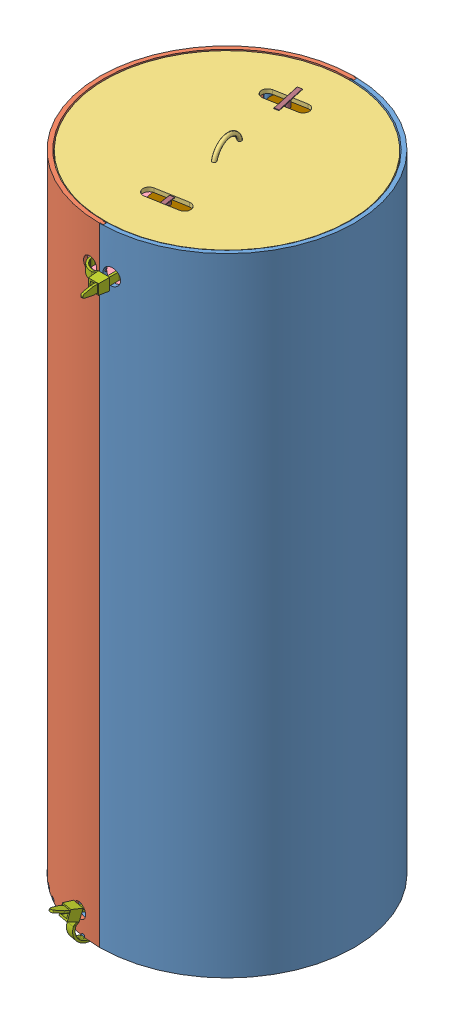
SolidWorks assembly Assemb_final, configuration Default. Lengths in mm.
Overall size (167.56 319.54 166.94).
85 component instances, 50 part files, 17 mates.
Components (placement in the parent):
- Part1-1: Part1 [Default] at (122.3324 -8.1399 242.6336) size (125 308 125)
- sec_cylinder-1: sec_cylinder [Default] at (122.3324 -8.1399 242.6336) size (64 308 125)
- Part2-1: Part2 [Default] at (-13.2425 297.5983 266.88) x (-0.176048 0 -0.984382) z (0.984382 0 -0.176048) size (120 9 120)
- Part3-1: Part3 [Default] at (123.4602 107.8147 242.6336) x (0.837662 0 -0.546189) z (0.546189 0 0.837662) size (120 1.5 120)
- Adafruit BMP388 Breakout.step-1: Adafruit BMP388 Breakout.step [Default] at (72.5042 113.6075 224.1927) size (21.59 11.6 16.51)
  - MalePinHeader.step-1: MalePinHeader.step [Default] at (14.8329 -4.1349 22.0117) size (2.54 11.54 2.54)
  - MalePinHeader.step-2: MalePinHeader.step [Default] at (9.7562 -4.1349 22.0162) size (2.54 11.54 2.54)
  - MalePinHeader.step-3: MalePinHeader.step [Default] at (7.2156 -4.1349 21.9989) size (2.54 11.54 2.54)
  - MalePinHeader.step-4: MalePinHeader.step [Default] at (-0.4008 -4.1349 21.997) size (2.54 11.54 2.54)
  - MalePinHeader.step-5: MalePinHeader.step [Default] at (-2.9499 -4.1349 22.0117) size (2.54 11.54 2.54)
  - MalePinHeader.step-6: MalePinHeader.step [Default] at (12.3028 -4.1349 22.0061) size (2.54 11.54 2.54)
  - MalePinHeader.step-7: MalePinHeader.step [Default] at (2.1379 -4.1349 22.0105) size (2.54 11.54 2.54)
  - MalePinHeader.step-8: MalePinHeader.step [Default] at (4.6865 -4.1349 22.0155) size (2.54 11.54 2.54)
  - Bosch BMP388.step-1: Bosch BMP388.step [Default] at (6.2406 0.0201 15.767) size (2 0.75 2)
  - SOD-523F Package.step-1: SOD-523F Package.step [Default] at (9.3077 0.02 14.6929) size (1.6 0.7 0.8)
  - SOT-23-5.step-1: SOT-23-5.step [Default] at (-0.8779 0.02 16.4671) x (0 0 -1) z (1 0 0) size (2.8 1.45 2.9)
  - SOT-363.step-1: SOT-363.step [Default] at (11.8928 0.77 18.7503) size (2.1 1.1 2)
  - 0603 Isolated 4 Resistor Array.step-1: 0603 Isolated 4 Resistor Array.step [Default] at (14.3354 0.02 15.5451) x (0 0 1) z (0 1 0) size (3.2 1.6 0.61)
  - Capacitor 0805 T1.35 BN.step-1: Capacitor 0805 T1.35 BN.step [Default] at (-1.0453 0.695 18.8902) size (2.1 1.35 1.35)
  - Capacitor 0805 T1.35 BN.step-2: Capacitor 0805 T1.35 BN.step [Default] at (1.1606 0.695 16.384) x (0 0 -1) z (1 0 0) size (2.1 1.35 1.35)
  - Capacitor 0603 T0.9 BN.step-1: Capacitor 0603 T0.9 BN.step [Default] at (3.9082 0.47 16.3763) x (0 0 1) z (-1 0 0) size (1.7 0.9 0.9)
  - Resistor 0603.step-1: Resistor 0603.step [Default] at (12.1248 -0.03 14.2385) size (1.7 0.55 0.9)
  - Resistor 0603.step-2: Resistor 0603.step [Default] at (6.6546 -0.03 18.7736) x (0 0 1) z (-1 0 0) size (1.7 0.55 0.9)
  - Adafruit BMP388 Breakout.step-1: Adafruit BMP388 Breakout.step [Default] at origin size (21.59 1.62 16.51)
- GyroScope-1: GyroScope [Default] at (-4.1281 -56.9334 -60.2678) size (60 115.04 60)
  - gyro-1: gyro [Default] at (126.3891 49.8515 303.0815) size (39 115.04 40)
  - flywheel-1: flywheel [Default] at (126.3891 79.8515 318.2042) size (60 60 10)
  - flywheel-2: flywheel [Default] at (150.3891 129.8515 303.0815) x (0 0 1) z (-1 0 0) size (60 60 10)
- Quectel MC90.step-1: Quectel MC90.step [Default] at (155.6186 113.6846 250.3473) x (1 0 0) z (0 -0.999962 0.008727) size (15.02 25.62 2.3)
- Adafruit BNO055 STEMMA QT.step-1: Adafruit BNO055 STEMMA QT.step [Default] at (122.2051 109.2869 215.6894) x (1 0 0) z (0 -0.999962 0.008727) size (25.4 20.32 4.6)
  - SOD-123.step-1: SOD-123.step [Default] at (7.2106 -3.9982 1.65) x (-1 0 0) z (0 0 1) size (3.85 1.7 1.36)
    - SOD-123_1.step-1: SOD-123_1.step [Default] at origin size (3.85 1.7 1.36)
      - Cathode.step-1: Cathode.step [Default] at origin size (1.45 0.65 0.7)
      - Anode.step-1: Anode.step [Default] at origin size (1.45 0.65 0.7)
      - Cathode Bar.step-1: Cathode Bar.step [Default] at origin size (0.3 1.5 0.01)
      - Body.step-1: Body.step [Default] at origin size (2.85 1.7 1.25)
  - Printed Circuit Board.step-1: Printed Circuit Board.step [Default] at origin size (25.4 20.32 1.65)
  - BNO055-9axis-IMU.step-1: BNO055-9axis-IMU.step [Default] at (-0.775 -1.2322 1.65) x (0 -1 0) z (0 0 1) size (5.2 3.8 1.18)
  - Crystal_XTAL3215_32.768KHz.step-1: Crystal_XTAL3215_32.768KHz.step [Default] at (2.5018 -0.2424 1.65) x (0 1 0) z (0 0 1) size (3.2 1.5 0.9)
  - SOT23-5.step-1: SOT23-5.step [Default] at (-5.3675 -3.3806 1.6297) x (0 -1 0) z (0 0 1) size (2.84 3.01 1.19)
  - SOT23-6.step-1: SOT23-6.step [Default] at (3.2455 -3.4306 1.2743) size (1.98 2.11 0.83)
  - LED 0603 single color.step-1: LED 0603 single color.step [Default] at (-11.0696 4.2146 1.6576) x (0 1 0) z (0 0 1) size (0.79 1.6 0.71)
  - CAPC-0805-T0.95-BN.step-1: CAPC-0805-T0.95-BN.step [Default] at (-4.9887 0.9204 1.65) size (2.1 1.35 0.95)
  - CAPC-0805-T0.95-BN.step-2: CAPC-0805-T0.95-BN.step [Default] at (-8.7494 -4.1689 1.65) size (2.1 1.35 0.95)
  - CAPC-0603-T0.9-BN.step-1: CAPC-0603-T0.9-BN.step [Default] at (-5.2459 -0.7391 1.65) size (1.7 0.9 0.9)
  - CAPC-0603-T0.9-BN.step-2: CAPC-0603-T0.9-BN.step [Default] at (2.199 2.9893 1.65) size (1.7 0.9 0.9)
  - CAPC-0603-T0.9-BN.step-3: CAPC-0603-T0.9-BN.step [Default] at (4.3017 -0.0333 1.65) x (0 1 0) z (0 0 1) size (1.7 0.9 0.9)
  - CAPC-0603-T0.9-BN.step-4: CAPC-0603-T0.9-BN.step [Default] at (5.6826 -0.393 1.65) x (0 1 0) z (0 0 1) size (1.7 0.9 0.9)
  - RESC-0603.step-1: RESC-0603.step [Default] at (10.9068 -4.1944 1.65) size (1.7 0.9 0.55)
  - YC164_RESPACK.step-1: YC164_RESPACK.step [Default] at (-3.6288 2.1707 1.65) size (3.2 1.6 0.61)
  - YC164_RESPACK.step-2: YC164_RESPACK.step [Default] at (7.5951 4.3154 1.65) x (-1 0 0) z (0 0 1) size (3.2 1.6 0.61)
  - qwicc.step-1: qwicc.step [Default] at (-8.624 0.0086 1.345) x (0 -1 0) z (-1 0 0) size (6 2.96 4.95)
  - qwicc.step-2: qwicc.step [Default] at (8.5749 0.0141 1.345) x (0 1 0) z (1 0 0) size (6 2.96 4.95)
- Teensy_4.0_Assembly.STEP-1: Teensy_4.0_Assembly.STEP [Default] at (151.6361 100.2968 236.9553) size (36.75 4.12 17.7)
  - Teensy_4.0_PCB.STEP-1: Teensy_4.0_PCB.STEP [Default] at (-32.9666 11.0804 9.3926) size (35.5 1.4 17.7)
  - Micro USB-B Female 5Pin SMD.STEP-1: Micro USB-B Female 5Pin SMD.STEP [Default] at (-46.3666 13.7054 9.3926) x (0 0 1) z (0 1 0) size (8.05 5.8 3.73)
  - NXP iMXRT1062.STEP-1: NXP iMXRT1062.STEP [Default] at (-33.7166 12.4804 9.3926) x (0 0 1) z (-1 0 0) size (10 1.52 10)
  - SKRPACE010 v4.STEP-1: SKRPACE010 v4.STEP [Default] at (-22.5666 12.5304 7.7926) size (4.89 2.55 3.2)
- XBee Pro 60mW-1: XBee Pro 60mW [Default] at (119.722 119.2557 282.5324) size (33 30 25)
  - XBee Pro 60mW PCB-1: XBee Pro 60mW PCB [Default] at (-26.8117 -5.3484 14.4414) size (33 25 25)
  - 10x Pinheader Male-1: 10x Pinheader Male [Default] at (-19.6678 -5.3484 -9.4947) x (0 0 -1) z (-1 0 0) size (2 9 20)
  - 10x Pinheader Male-2: 10x Pinheader Male [Default] at (-19.6678 -5.3484 13.3775) x (0 0 -1) z (-1 0 0) size (2 9 20)
- battery-1: battery [Default] at (150.4665 2.4074 219.4102) x (-0.017452 -0.000536 -0.999848) z (0.000067 1 -0.000537) size (18.5 66.3 18.5)
- Holder-1: Holder [Default] at (115.9229 2.41 220.0131) x (0.000076 1 0) z (-0.999848 0.000076 0.017452) size (19.6 19.6 65.3)
- Part3-2: Part3 [Default] at (121.9628 250.4618 241.7519) x (0.837662 0 -0.546189) z (0.546189 0 0.837662) size (120 1.5 120)
- Part4-1: Part4 [Default] at (153.5184 261.7969 211.3128) x (0.06427 0.816627 0.573576) z (-0.045002 -0.571808 0.819152) size (29.79 50 29.79)
- Part27-1: Part27 [Default] at (139.5551 277.3003 211.1754) x (0.991862 0.117619 0.048733) z (0.058241 -0.078807 -0.995187) size (1 35 35)
- ZIP TIE-1: ZIP TIE [Default] at (54.2549 -9.6928 243.0635) x (-0.008299 0.002697 0.999962) z (-0.95102 0.309005 -0.008727) size (5.87 14.74 24.68)
- ZIP TIE-2: ZIP TIE [Default] at (110.9342 -9.6928 309.7514) x (0.983329 0.002697 0.181815) z (-0.173737 0.309005 0.935057) size (5.87 14.74 24.68)
- ZIP TIE-3: ZIP TIE [Default] at (54.2549 -9.6928 242.2037) x (0.008299 -0.002697 0.999962) z (-0.95102 0.309005 0.008727) size (5.87 14.74 24.68)
- ZIP TIE-4: ZIP TIE [Default] at (110.9342 -9.6928 175.5157) x (-0.983329 -0.002697 0.181815) z (-0.173737 0.309005 -0.935057) size (5.87 14.74 24.68)
- Servo_Ass-1: Servo_Ass [Default] at (164.2075 263.1188 247.2111) x (-0.515317 0 0.857) z (-0.857 0 -0.515317) size (78.72 44 71.24)
  - Part5-1: Part5 [Default] at (17.0909 -10.1571 39.0169) size (15 42 15)
  - servo_cap1-1: servo_cap1 [Default] at (-6.644 28.8429 11.7968) x (-0.653273 0 -0.757122) z (0.757122 0 -0.653273) size (17.16 5 89.16)
- 3202.step-1: 3202.step [Default] at (72.7608 -0.473 234.0694) x (1 0 0) z (0 -0.999962 0.008727) size (17.3 49.35 6.65)
- screw-1: screw [Default] at (113.7789 -8.4903 247.9991) size (3 9.54 3)
- screw-2: screw [Default] at (130.9927 -8.4903 247.5668) x (-0.5 0 -0.866025) z (0.866025 0 -0.5) size (3 9.54 3)
- screw-3: screw [Default] at (122.0114 -8.4903 232.8753) x (-0.5 0 0.866025) z (-0.866025 0 -0.5) size (3 9.54 3)
- Para_2-1: Para_2 [Default] at (185.3467 543.5019 211.729) size (514.47 802 514.47) (hidden)
- ZIP TIE-5: ZIP TIE [Default] at (114.7994 279.5546 308.1894) x (-0.008727 -0.999962 0) z (0 0 1) size (5.87 14.74 24.68)
- ZIP TIE-6: ZIP TIE [Default] at (130.148 279.9163 174.602) x (0 -0.999962 0.008727) z (0 -0.008727 -0.999962) size (5.87 14.74 24.68)
- bracket-1: bracket [Default] at (121.9628 251.9618 241.7519) x (0.857 0 0.515317) z (-0.515317 0 0.857) size (24.04 10 24.04)
- rotate_servo_lid_release-1: rotate_servo_lid_release [Default] at (128.1526 298.9618 277.025) x (-0.147949 0 -0.988995) z (-0.988995 0 0.147949) size (15 5.16 2.32)
- rotate_servo_lid_release-2: rotate_servo_lid_release [Default] at (116.2519 300.4289 206.5218) x (0.21644 0 0.976296) z (0.976259 -0.008727 -0.216431) size (15 5.16 2.32)
- Para_2-2: Para_2 [Default] at (123.7795 953.082 242.737) size (514.47 802 514.47) (hidden)
Mates (geometry in assembly coordinates):
- Concentric1: concentric aligned: cylinder of Part1-1 through (122.3324 299.8601 242.6336) axis (0 -1 0) radius 60.5; cylinder of Part2-1 through (122.3324 299.8601 242.6336) axis (0 -1 0) radius 60
- Coincident1: coincident aligned: plane of Part1-1 through (122.3324 299.8601 242.6336) normal (0 1 0); plane of Part2-1 through (122.3324 299.8601 242.6336) normal (0 1 0)
- Concentric2: concentric aligned: cylinder of sec_cylinder-1 through (122.3324 299.8601 242.6336) axis (0 -1 0) radius 60.49; cylinder of Part2-1 through (122.3324 299.8601 242.6336) axis (0 -1 0) radius 60
- Coincident2: coincident aligned: plane of sec_cylinder-1 through (122.3324 299.8601 242.6336) normal (0 1 0); plane of Part2-1 through (122.3324 299.8601 242.6336) normal (0 1 0)
- Tangent2: tangent anti-aligned: plane of Part1-1 through (94.8324 -8.1399 195.0022) normal (0.5 0 0.866025); cylinder of Part3-1 through (123.4602 109.3147 242.6336) axis (0 -1 0) radius 60
- Tangent3: tangent anti-aligned: plane of Part1-1 through (94.8324 -8.1399 290.265) normal (0.5 0 -0.866025); cylinder of Part3-1 through (132.3324 44.3601 242.6336) axis (0 -1 0) radius 60
- Coincident4: coincident anti-aligned: plane of Part1-1 through (96.0333 42.8601 200.0823) normal (0 1 0); plane of Part3-1 through (123.4602 107.8147 242.6336) normal (0 -1 0)
- Parallel1: parallel anti-aligned: plane of Part3-1 through (123.4602 109.3147 242.6336) normal (0 1 0); plane of Adafruit BMP388 Breakout.step-1/Adafruit BMP388 Breakout.step-1 through (79.7443 112.0375 241.6802) normal (0 -1 0)
- Concentric4: concentric anti-aligned: cylinder of battery-1 through (84.1766 2.4124 220.5673) axis (0.999848 -0.000076 -0.017452) radius 4.5; circle of Holder-1
- Coincident6: coincident anti-aligned: plane of Part1-1 through (123.8324 -8.1409 242.6336) normal (-1 0 0); plane of sec_cylinder-1 through (123.8324 299.8601 303.3836) normal (1 0 0)
- Parallel2: parallel anti-aligned: plane of Part2-1 through (122.3324 299.8601 242.6336) normal (0 1 0); plane of Servo_Ass-1/servo_cap1-1 through (112.7245 296.9618 206.7627) normal (0 1 0)
- Coincident9: coincident anti-aligned: plane of Part2-1 through (122.3324 299.8601 242.6336) normal (0 1 0); plane of Servo_Ass-1/servo_cap1-1 through (114.3092 304.7841 206.3822) normal (0 1 0)
- Parallel4: parallel anti-aligned: plane of Part3-2 through (121.9628 251.9618 241.7519) normal (0 1 0); plane of bracket-1 through (121.9628 251.9618 241.7519) normal (0 -1 0)
- Lock1: lock: unknown of Part1-1; unknown of Part3-2
- ProfileCenter2: profile center aligned: plane of bracket-1 through (121.9628 251.9618 241.7519) normal (0 -1 0); plane of Part3-2 through (121.9628 251.9618 241.7519) normal (0 1 0)
- ProfileCenter4: profile center anti-aligned: plane of Servo_Ass-1/Part5-1 through (121.9628 252.9618 241.7519) normal (0 -1 0); plane of bracket-1 through (121.9628 252.9618 241.7519) normal (0 1 0)
- ProfileCenter6: profile center anti-aligned: circle of rotate_servo_lid_release-1; plane of Servo_Ass-1/servo_cap1-1 through (128.1526 293.9618 277.025) normal (0 1 0)
